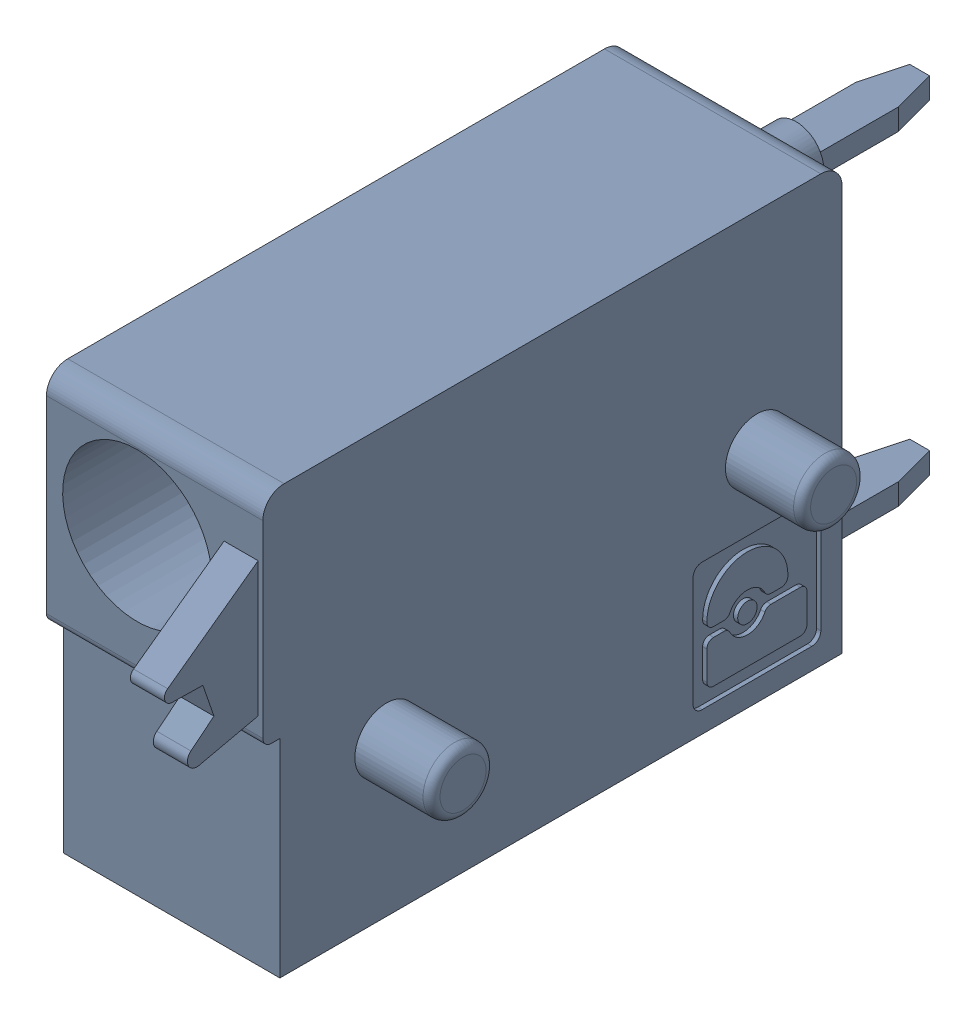
SolidWorks assembly J65, configuration Default. Lengths in mm.
Overall size (6.88 10 19.2).
2 component instances, 1 part files, 0 mates.
Components (placement in the parent):
- 1790348-1: 1790348 [Default] at (187.3251 -7.6199 0) x (0 1 0) z (1 0 0) size (10 19.2 6.88)
  - ffkds-v2-5.08-1: ffkds-v2-5.08 [Default] at (-23.7414 -38.158 -2.54) x (0 -1 0) z (0 0 1) size (19.2 10 6.88)
